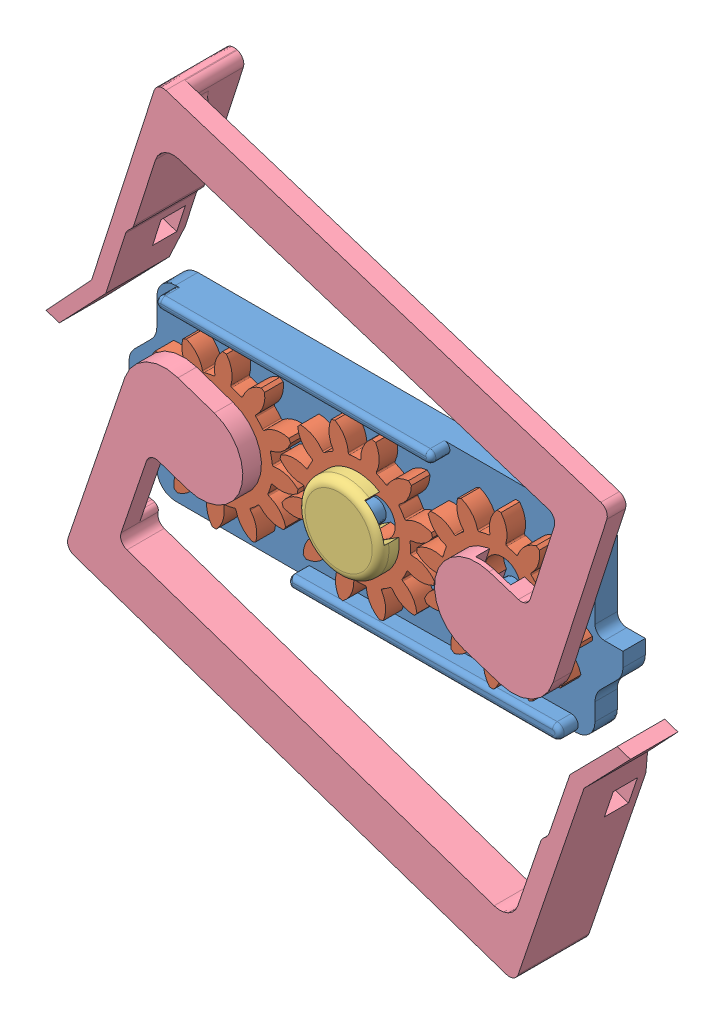
SolidWorks assembly WebCoupler, configuration Default. Lengths in mm.
Overall size (79.62 84.33 9.65).
7 component instances, 4 part files, 17 mates.
Components (placement in the parent):
- BasePlate-1: BasePlate [Default] at (-2.9894 14.8162 46.0364) size (67.3 25.47 7.37)
- WebGear-1: WebGear [Default] at (26.8556 27.5162 51.6244) x (0.543565 -0.839367 0) z (0 0 -1) size (20.81 20.81 2.54)
- WebGear-2: WebGear [Default] at (45.6516 27.5162 51.6244) x (0.952396 -0.304863 0) z (0 0 -1) size (20.81 20.81 2.54)
- WebGear-3: WebGear [Default] at (8.0596 27.5162 51.6244) x (-0.947012 0.321197 0) z (0 0 -1) size (20.81 20.81 2.54)
- CapturePlate-1: CapturePlate [Default] at (27.3503 28.4735 54.1644) x (0.543565 -0.839367 0) z (0 0 -1) size (11.42 11.3 5.08)
- WebArm-2: WebArm [Default] at (8.2988 26.4749 54.1644) x (-0.947012 0.321197 0) z (0 0 -1) size (68.64 37.46 9.65)
- WebArm-4: WebArm [Default] at (45.3945 28.5532 54.1644) x (0.952396 -0.304863 0) z (0 0 -1) size (68.64 37.46 9.65)
Mates (geometry in assembly coordinates):
- Coincident1: coincident anti-aligned: plane of BasePlate-1 through (-2.9894 14.8162 49.0844) normal (0 0 1); plane of WebGear-3 through (11.2164 30.4506 49.0844) normal (0 0 -1)
- Concentric2: concentric anti-aligned: cylinder of BasePlate-1 through (8.0596 27.5162 51.7514) axis (0 0 -1) radius 1.397; cylinder of WebGear-3 through (8.0596 27.5162 49.0844) axis (0 0 1) radius 1.524
- Coincident2: coincident anti-aligned: plane of BasePlate-1 through (-2.9894 14.8162 49.0844) normal (0 0 1); plane of WebGear-1 through (22.5593 27.1728 49.0844) normal (0 0 -1)
- Concentric3: concentric anti-aligned: cylinder of BasePlate-1 through (26.8556 27.5162 51.7514) axis (0 0 -1) radius 1.397; cylinder of WebGear-1 through (26.8556 27.5162 49.0844) axis (0 0 1) radius 1.524
- Coincident3: coincident anti-aligned: plane of BasePlate-1 through (-2.9894 14.8162 49.0844) normal (0 0 1); plane of WebGear-2 through (42.5457 24.528 49.0844) normal (0 0 -1)
- Concentric4: concentric anti-aligned: cylinder of BasePlate-1 through (45.6516 27.5162 51.7514) axis (0 0 -1) radius 1.397; cylinder of WebGear-2 through (45.6516 27.5162 49.0844) axis (0 0 1) radius 1.524
- GearMate5: gear = 3.048 : 3.048 mm: circle of WebGear-1; circle of WebGear-3
- GearMate6: gear = 3.048 : 3.048 mm: circle of WebGear-1; circle of WebGear-2
- Concentric7: concentric anti-aligned: circle of BasePlate-1; circle of CapturePlate-1
- Parallel2: parallel aligned: line of WebGear-1 through (28.6504 24.7446 49.0844) axis (-0.543565 0.839367 0); line of CapturePlate-1 through (28.6947 24.7733 49.0844) axis (-0.543565 0.839367 0)
- Coincident15: coincident anti-aligned: plane of WebGear-1 through (22.5593 27.1728 51.6244) normal (0 0 1); circle of CapturePlate-1
- Coincident17: coincident anti-aligned: plane of BasePlate-1 through (-2.9894 14.8162 49.0844) normal (0 0 1); plane of CapturePlate-1 through (29.2703 25.1461 49.0844) normal (0 0 -1)
- Coincident21: coincident: moEndPointRef_w of WebGear-3; moEndPointRef_w of WebArm-2
- Parallel5: parallel aligned: line of WebGear-3 through (4.9325 28.5768 51.6244) axis (0.947012 -0.321197 0); line of WebArm-2 through (4.949 28.5433 51.6244) axis (0.947012 -0.321197 0)
- Coincident24: coincident anti-aligned: plane of WebGear-3 through (11.2164 30.4506 51.6244) normal (0 0 1); circle of WebArm-2
- Coincident33: coincident: moEndPointRef_w of WebGear-2; moEndPointRef_w of WebArm-4
- Parallel7: parallel aligned: line of WebGear-2 through (48.7964 26.5095 51.6244) axis (-0.952396 0.304863 0); line of WebArm-4 through (48.7793 26.5427 51.6244) axis (-0.952396 0.304863 0)
